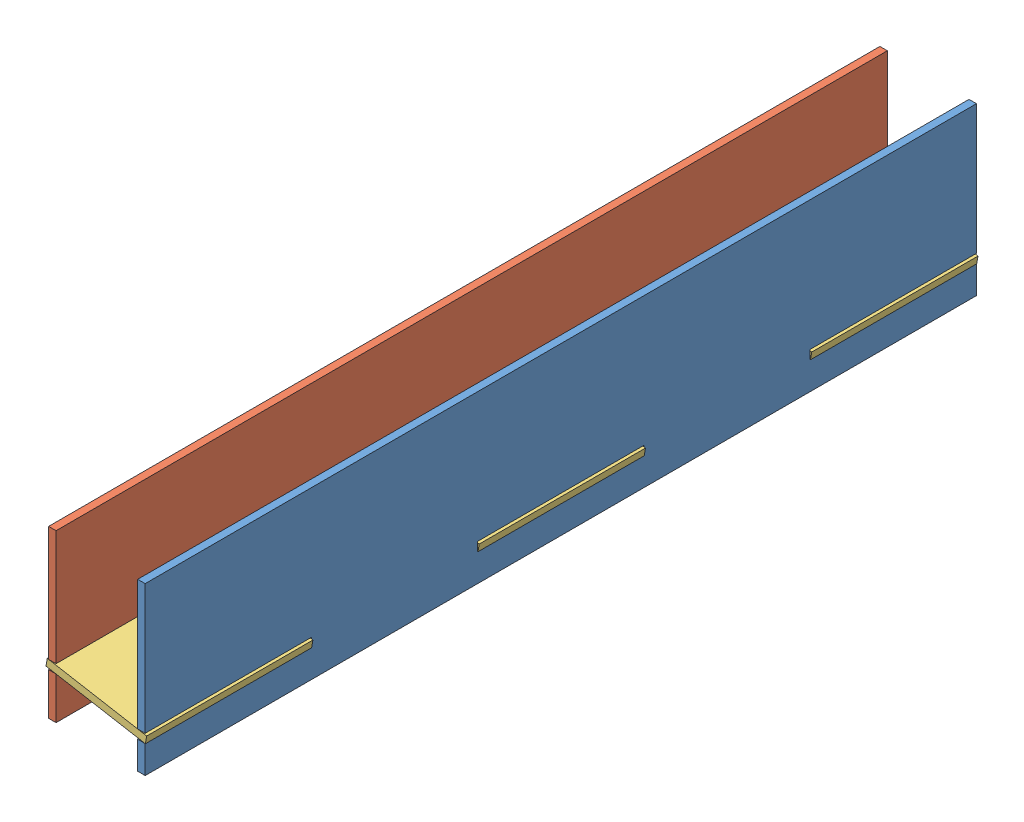
SolidWorks assembly Assem1, configuration Default. Lengths in mm.
Overall size (36.34 60.46 300).
3 component instances, 3 part files, 2 mates.
Components (placement in the parent):
- side_wall_1-1: side_wall_1 [Default] at (149.1075 148.6932 215.3148) x (0 0 -1) z (0 -1 0) size (300 2.7 60)
- side_wall_2-1: side_wall_2 [Default] at (116.949 149.1552 215.3148) x (0 0 -1) z (0 -1 0) size (300 2.7 60)
- coin_plate-1: coin_plate [Default] at (133.948 131.8433 215.3148) x (0 0 -1) z (0.9848 -0.17369 0) size (300 2.7 36.42)
Mates (geometry in assembly coordinates):
- Coincident12: coincident: line of side_wall_2-1 through (119.649 134.3652 305.3148) axis (0 0 1); plane of coin_plate-1 through (133.948 131.8433 215.3148) normal (-0.17369 -0.9848 0)
- Coincident14: coincident: line of side_wall_1-1 through (149.1075 131.9112 365.3148) axis (0 0 -1); plane of coin_plate-1
